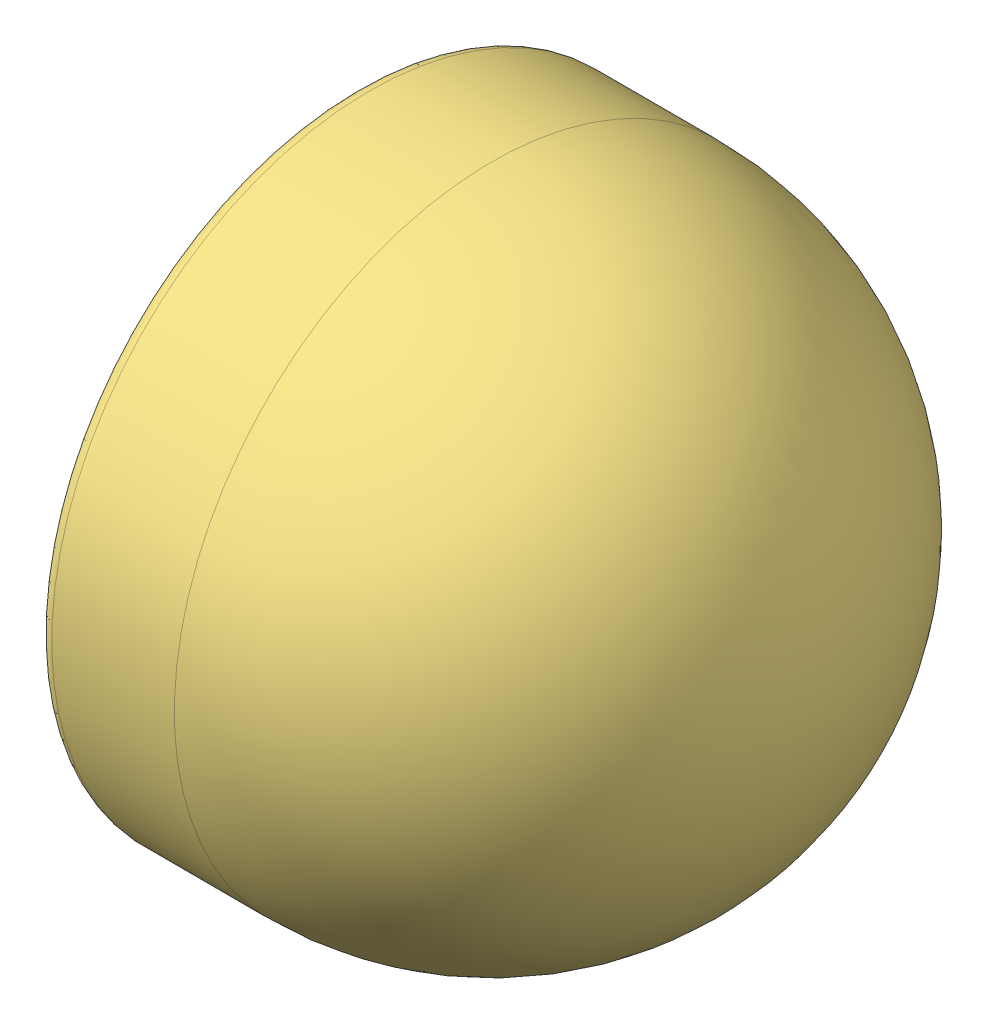
SolidWorks assembly Assem1, configuration Default. Lengths in mm.
Overall size (113.96 184.15 184.15).
4 component instances, 4 part files, 7 mates.
Components (placement in the parent):
- bulb cover-1: bulb cover [Default] at (135.9073 67.4118 61.6172) size (30.99 130 130)
- front light bulb-1: front light bulb [Default] at (135.4073 67.4118 61.6172) x (1 0 0) z (0 0.610151 0.792285) size (25.36 19 19)
- front light case-1: front light case [Default] at (192.031 67.4118 61.6172) x (1 0 0) z (0 0.397983 0.917393) size (100 140 140)
- front light glass-1: front light glass [Default] at (127.9143 67.4118 61.6172) x (1 0 0) z (0 0.015242 0.999884) size (33.85 128 128)
Mates (geometry in assembly coordinates):
- Concentric1: concentric: cylinder of assembly; cylinder of assembly; cylinder of bulb cover-1 through (25.4909 67.4118 61.6172) axis (-1 0 0) radius 5; cylinder of front light bulb-1 through (135.4073 67.4118 61.6172) axis (-1 0 0) radius 4
- Coincident1: coincident: plane of assembly; plane of assembly; plane of bulb cover-1 through (135.9073 72.4118 61.6172) normal (-1 0 0); plane of front light bulb-1 through (135.9073 71.3733 58.5664) normal (1 0 0)
- Concentric2: concentric: cylinder of assembly; cylinder of assembly; cylinder of bulb cover-1 through (25.4909 67.4118 61.6172) axis (-1 0 0) radius 65; cylinder of front light glass-1 through (-34.4994 67.4118 61.6172) axis (-1 0 0) radius 64
- Coincident3: coincident: plane of assembly; plane of assembly; plane of bulb cover-1 through (111.9143 131.4118 61.6172) normal (-1 0 0); plane of front light glass-1 through (111.9143 131.4044 60.6417) normal (1 0 0)
- Concentric3: concentric: cylinder of bulb cover-1 through (25.4909 67.4118 61.6172) axis (-1 0 0) radius 65; cylinder of ? through (325.5065 67.4118 61.6172) axis (-1 0 0) radius 70
- Concentric5: concentric: circle of bulb cover-1; circle of ?
- Coincident5: coincident: sphere of assembly; circle of assembly; sphere of bulb cover-1; circle of front light case-1
